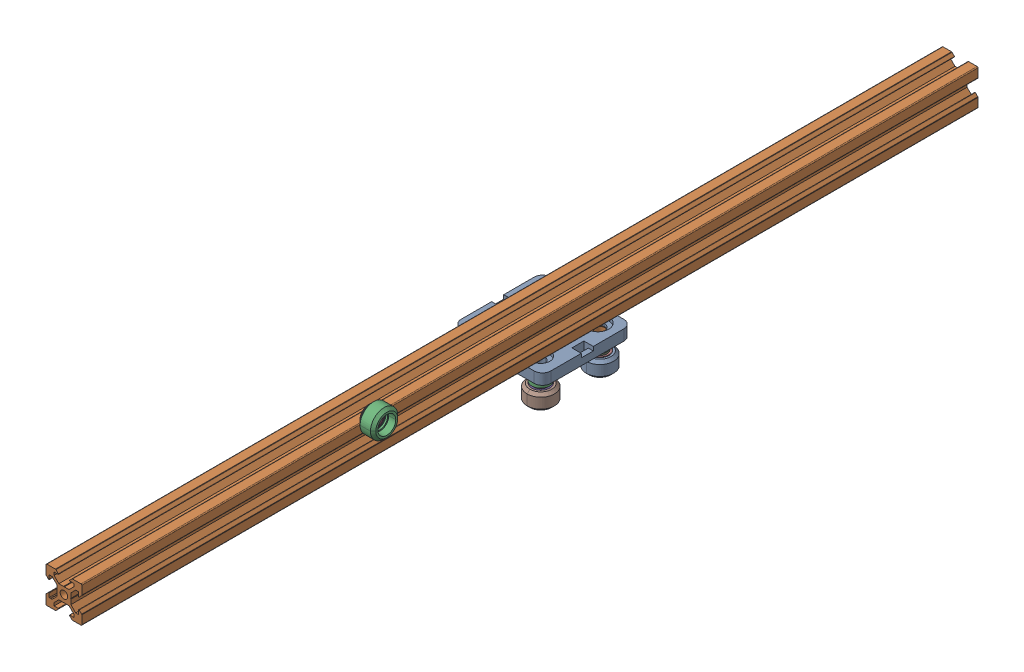
SolidWorks assembly Extrusion Wheel Estimation, configuration Default. Lengths in mm.
Overall size (118.94 108.25 500).
16 component instances, 7 part files, 36 mates.
Components (placement in the parent):
- Mini-V-Gantry-Plate-1: Mini-V-Gantry-Plate [Default] at (-28.8153 -53.1382 -104.4778) size (50 6 50)
- Eccentric-Spacer-6mm-1: Eccentric-Spacer-6mm [Default] at (-13.8153 -54.1382 -120.4278) x (0.837169 0 0.546944) z (0.546944 0 -0.837169) size (10 8.5 9.7)
- Aluminum Spacers-1: Aluminum Spacers [Default] at (-13.8153 -53.1382 -88.5278) x (1 0 0) z (0 -1 0) size (10 10 6)
- Mini-V-Precision-Shim-3: Mini-V-Precision-Shim [Default] at (-13.8153 -60.1382 -88.5278) size (8 1 8) (hidden)
- Mini-V-Bearing-3: Mini-V-Bearing [Default] at (-13.8153 -62.2382 -88.5278) x (0 -1 0) z (0 0 1) size (4.2 10 10) (hidden)
- Mini-V-Precision-Shim-4: Mini-V-Precision-Shim [Default] at (-13.8153 -65.3382 -88.5278) size (8 1 8) (hidden)
- Mini-V-Bearing-4: Mini-V-Bearing [Default] at (-13.8153 -67.4382 -88.5278) x (0 -1 0) z (0 0 1) size (4.2 10 10) (hidden)
- Mini-V-Wheel-2: Mini-V-Wheel [Default] at (-13.8153 -64.5382 -88.5278) x (0 1 0) z (0 0 1) size (8.8 15.23 15.23) (hidden)
- Mini-V-Precision-Shim-5: Mini-V-Precision-Shim [Default] at (-13.3832 -60.1382 -121.0891) size (8 1 8) (hidden)
- Mini-V-Bearing-5: Mini-V-Bearing [Default] at (-13.3832 -62.2382 -121.0891) x (0 -1 0) z (0 0 1) size (4.2 10 10) (hidden)
- Mini-V-Bearing-6: Mini-V-Bearing [Default] at (-13.3832 -67.4382 -121.0891) x (0 -1 0) z (0 0 1) size (4.2 10 10) (hidden)
- Mini-V-Precision-Shim-6: Mini-V-Precision-Shim [Default] at (-13.3832 -65.3382 -121.0891) size (8 1 8) (hidden)
- Mini-V-Wheel-3: Mini-V-Wheel [Default] at (-13.3832 -64.8382 -121.0891) x (0 1 0) z (0 0 1) size (8.8 15.23 15.23) (hidden)
- T-V-Slot-Aluminium-Extrusion_v2-1: T-V-Slot-Aluminium-Extrusion_v2 [Default] at (39.4189 23.809 -769.2371) size (20 20 500)
- Mini-V-Wheel-4: Mini-V-Wheel [Default] at (60.7219 41.4894 76.3236) size (8.8 15.23 15.23)
- Mini-V-Bearing-7: Mini-V-Bearing [Default] at (57.2397 41.4894 76.3236) size (4.2 10 10)
Mates (geometry in assembly coordinates):
- Concentric2: concentric anti-aligned: circle of Mini-V-Precision-Shim-1; circle of Mini-V-Wheel-1
- Concentric3: concentric anti-aligned: cylinder of Mini-V-Bearing-1 through (19.786 -39.1448 -42.612) axis (0 -1 0) radius 2.5; circle of Mini-V-Precision-Shim-1
- Concentric4: concentric aligned: circle of Mini-V-Gantry-Plate-1; circle of Eccentric-Spacer-6mm-1
- Coincident2: coincident anti-aligned: plane of Mini-V-Gantry-Plate-1 through (-49.1803 -53.1382 -124.8428) normal (0 -1 0); plane of Eccentric-Spacer-6mm-1 through (-13.8153 -53.1382 -120.4278) normal (0 1 0)
- Concentric5: concentric anti-aligned: circle of Eccentric-Spacer-6mm-1; circle of Mini-V-Precision-Shim-2
- Coincident4: coincident anti-aligned: plane of Eccentric-Spacer-6mm-1 through (-13.8153 -59.1382 -120.4278) normal (0 -1 0); plane of Mini-V-Precision-Shim-2 through (19.786 -30.8448 -42.612) normal (0 1 0)
- Concentric6: concentric anti-aligned: circle of Mini-V-Precision-Shim-2; circle of Mini-V-Bearing-2
- Coincident6: coincident anti-aligned: plane of Mini-V-Precision-Shim-2 through (19.786 -31.8448 -42.612) normal (0 -1 0); plane of Mini-V-Bearing-2 through (21.879 -31.8448 -41.2447) normal (0 1 0)
- Concentric7: concentric aligned: circle of Mini-V-Precision-Shim-1; circle of Mini-V-Bearing-2
- Coincident8: coincident anti-aligned: plane of Mini-V-Precision-Shim-1 through (19.786 -36.0448 -42.612) normal (0 1 0); plane of Mini-V-Bearing-2 through (21.879 -36.0448 -41.2447) normal (0 -1 0)
- Coincident9: coincident anti-aligned: plane of Mini-V-Bearing-1 through (22.286 -37.0448 -42.612) normal (0 1 0); plane of Mini-V-Precision-Shim-1 through (19.786 -37.0448 -42.612) normal (0 -1 0)
- Concentric8: concentric aligned: circle of Mini-V-Wheel-1; circle of Mini-V-Precision-Shim-2
- Coincident12: coincident aligned: plane of Mini-V-Wheel-1 through (24.786 -31.8448 -42.612) normal (0 1 0); plane of Mini-V-Bearing-2 through (23.637 -31.8448 -40.0961) normal (0 1 0)
- Concentric9: concentric anti-aligned: circle of Mini-V-Gantry-Plate-1; circle of Aluminum Spacers-1
- Coincident14: coincident anti-aligned: plane of Mini-V-Gantry-Plate-1 through (-49.1803 -53.1382 -124.8428) normal (0 -1 0); plane of Aluminum Spacers-1 through (-13.8153 -53.1382 -88.5278) normal (0 1 0)
- Concentric10: concentric anti-aligned: circle of Aluminum Spacers-1; circle of Mini-V-Precision-Shim-3
- Coincident15: coincident anti-aligned: plane of Aluminum Spacers-1 through (-13.8153 -59.1382 -88.5278) normal (0 -1 0); plane of Mini-V-Precision-Shim-3 through (-13.8153 -59.1382 -88.5278) normal (0 1 0)
- Concentric11: concentric anti-aligned: circle of Mini-V-Precision-Shim-3; circle of Mini-V-Bearing-3
- Coincident17: coincident anti-aligned: plane of Mini-V-Precision-Shim-3 through (-13.8153 -60.1382 -88.5278) normal (0 -1 0); plane of Mini-V-Bearing-3 through (-11.3153 -60.1382 -88.5278) normal (0 1 0)
- Concentric12: concentric anti-aligned: circle of Mini-V-Bearing-3; circle of Mini-V-Precision-Shim-4
- Coincident19: coincident anti-aligned: plane of Mini-V-Bearing-3 through (-11.3153 -64.3382 -88.5278) normal (0 -1 0); plane of Mini-V-Precision-Shim-4 through (-13.8153 -64.3382 -88.5278) normal (0 1 0)
- Concentric13: concentric anti-aligned: circle of Mini-V-Precision-Shim-4; circle of Mini-V-Bearing-4
- Coincident21: coincident anti-aligned: plane of Mini-V-Precision-Shim-4 through (-13.8153 -65.3382 -88.5278) normal (0 -1 0); plane of Mini-V-Bearing-4 through (-11.3153 -65.3382 -88.5278) normal (0 1 0)
- Concentric14: concentric anti-aligned: circle of Mini-V-Bearing-4; circle of Mini-V-Wheel-2
- Coincident22: coincident aligned: plane of Mini-V-Bearing-3 through (-9.2153 -60.1382 -88.5278) normal (0 1 0); plane of Mini-V-Wheel-2 through (-18.8153 -60.1382 -88.5278) normal (0 1 0)
- Concentric15: concentric anti-aligned: circle of Eccentric-Spacer-6mm-1; circle of Mini-V-Precision-Shim-5
- Coincident24: coincident anti-aligned: plane of Eccentric-Spacer-6mm-1 through (-13.8153 -59.1382 -120.4278) normal (0 -1 0); plane of Mini-V-Precision-Shim-5 through (-13.3832 -59.1382 -121.0891) normal (0 1 0)
- Concentric16: concentric anti-aligned: circle of Mini-V-Precision-Shim-5; circle of Mini-V-Bearing-5
- Coincident26: coincident anti-aligned: plane of Mini-V-Precision-Shim-5 through (-13.3832 -60.1382 -121.0891) normal (0 -1 0); plane of Mini-V-Bearing-5 through (-10.8832 -60.1382 -121.0891) normal (0 1 0)
- Concentric17: concentric anti-aligned: circle of Mini-V-Bearing-5; circle of Mini-V-Precision-Shim-6
- Concentric18: concentric anti-aligned: circle of Mini-V-Bearing-6; circle of Mini-V-Precision-Shim-6
- Concentric19: concentric anti-aligned: circle of Mini-V-Bearing-6; circle of Mini-V-Wheel-3
- Concentric20: concentric aligned: circle of Mini-V-Wheel-4; circle of Mini-V-Bearing-7
- Coincident35: coincident aligned: plane of Mini-V-Precision-Shim-6 through (-13.3832 -64.3382 -121.0891) normal (0 1 0); circle of Mini-V-Wheel-3
- Coincident36: coincident anti-aligned: plane of Mini-V-Bearing-5 through (-10.8832 -64.3382 -121.0891) normal (0 -1 0); plane of Mini-V-Wheel-3 through (-17.7032 -64.3382 -121.0891) normal (0 1 0)
- Coincident37: coincident anti-aligned: plane of Mini-V-Bearing-6 through (-8.7832 -65.3382 -121.0891) normal (0 1 0); plane of Mini-V-Wheel-3 through (-17.7032 -65.3382 -121.0891) normal (0 -1 0)
